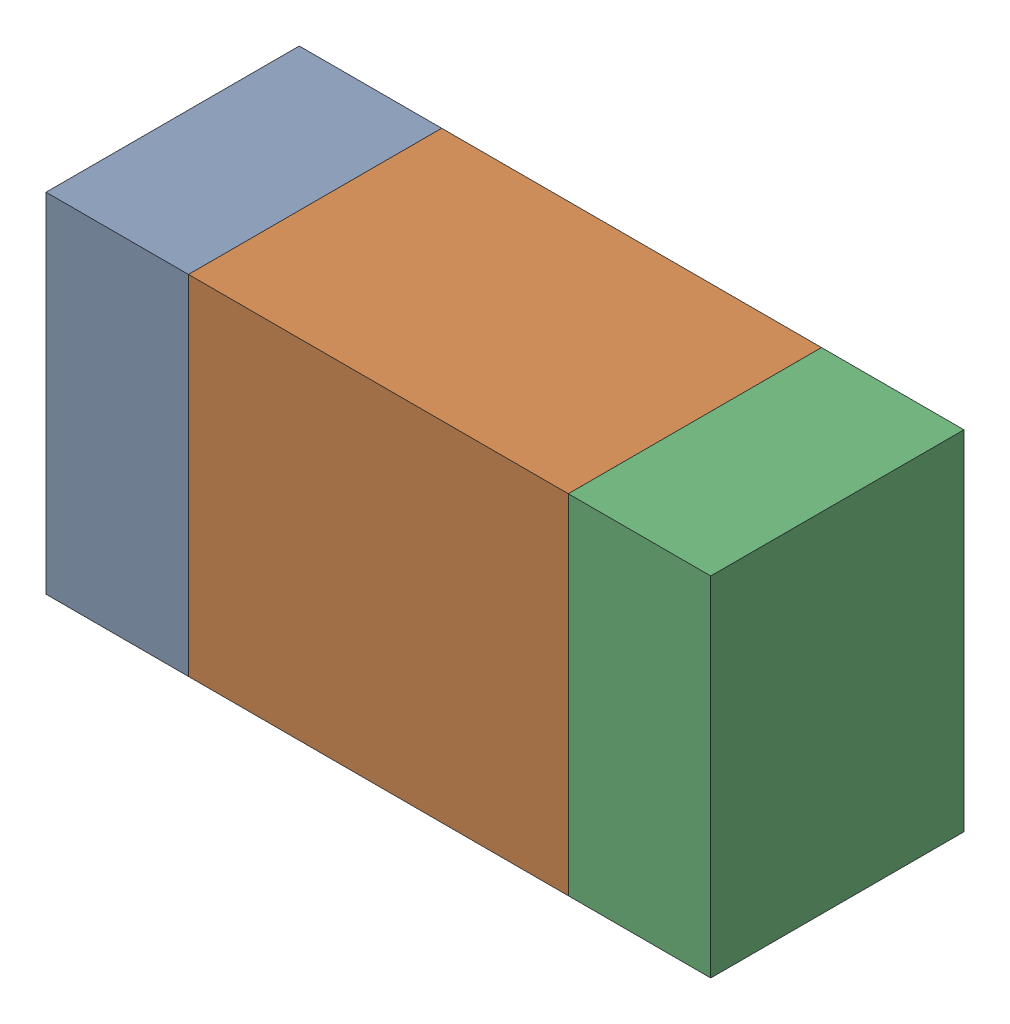
SolidWorks assembly R507_2PCB, configuration Default. Lengths in mm.
Overall size (1.05 0.55 0.4).
6 component instances, 2 part files, 0 mates.
Components (placement in the parent):
- 854785432-1: 854785432 [Default] at (148.8127 85.768 0) size (0.22 0.55 0.4)
  - Extruded-1: Extruded [Default] at origin size (0.22 0.55 0.4)
- 854785568-1: 854785568 [Default] at (149.2252 85.768 0) size (0.6 0.55 0.4)
  - Extruded_2-1: Extruded_2 [Default] at origin size (0.6 0.55 0.4)
- 854785432-2: 854785432 [Default] at (149.6377 85.768 0) size (0.22 0.55 0.4)
  - Extruded-1: Extruded [Default] at origin size (0.22 0.55 0.4)
